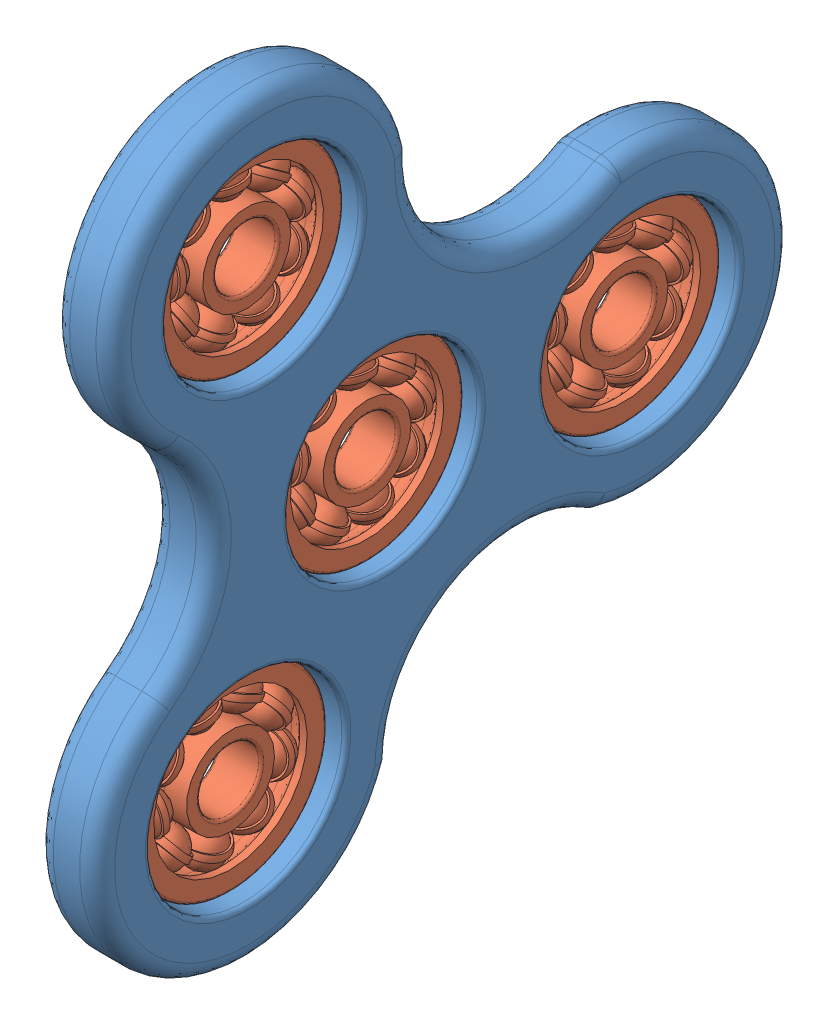
SolidWorks assembly asemspinner, configuration Default. Lengths in mm.
Overall size (7.23 89.78 83.98).
5 component instances, 2 part files, 10 mates.
Components (placement in the parent):
- fildeg spiner-1: fildeg spiner [Default] at (3.5 0 0) x (0 0.998158 -0.060674) z (1 0 0) size (85.14 78.96 7.23)
- FINAl_SPINNER-1: FINAl_SPINNER [BS 6267 ABB - 827 - Full,DE,AC,Full_68] at (2.5 -24.815 15.5658) x (1 0 0) z (0 -0.702747 -0.71144) size (5 22 22)
- FINAl_SPINNER-2: FINAl_SPINNER [BS 6267 ABB - 827 - Full,DE,AC,Full_68] at (2.5 25.8879 13.7075) x (1 0 0) z (0 0.595884 0.803071) size (5 22 22)
- FINAl_SPINNER-3: FINAl_SPINNER [BS 6267 ABB - 827 - Full,DE,AC,Full_68] at (2.5 -1.0729 -29.2733) x (1 0 0) z (0 0.992473 0.122465) size (5 22 22)
- FINAl_SPINNER-4: FINAl_SPINNER [BS 6267 ABB - 827 - Full,DE,AC,Full_68] at (2.5 0 0) x (1 0 0) z (0 -0.60569 0.795701) size (5 22 22)
Mates (geometry in assembly coordinates):
- Concentric1: concentric anti-aligned: cylinder of fildeg spiner-1 through (7 0 0) axis (-1 0 0) radius 11; cylinder of FINAl_SPINNER-4 through (-18.1375 0 0) axis (1 0 0) radius 5.025
- Coincident2: coincident aligned: plane of fildeg spiner-1 through (0 0 0) normal (-1 0 0); plane of FINAl_SPINNER-4 through (0 7.5393 5.7389) normal (-1 0 0)
- Concentric5: concentric anti-aligned: cylinder of fildeg spiner-1 through (7 25.8879 13.7075) axis (-1 0 0) radius 11.2096; cylinder of FINAl_SPINNER-2 through (-18.1375 25.8879 13.7075) axis (1 0 0) radius 11
- Coincident3: coincident aligned: plane of fildeg spiner-1 through (0 0 0) normal (-1 0 0); plane of FINAl_SPINNER-2 through (0 33.497 8.0615) normal (-1 0 0)
- Concentric6: concentric anti-aligned: cylinder of fildeg spiner-1 through (7 -1.0729 -29.2733) axis (-1 0 0) radius 11.2096; cylinder of FINAl_SPINNER-3 through (-18.1375 -1.0729 -29.2733) axis (1 0 0) radius 11
- Coincident4: coincident aligned: plane of fildeg spiner-1 through (0 0 0) normal (-1 0 0); plane of FINAl_SPINNER-3 through (0 0.0874 -38.677) normal (-1 0 0)
- Concentric7: concentric anti-aligned: cylinder of fildeg spiner-1 through (7 -24.815 15.5658) axis (-1 0 0) radius 11.2096; cylinder of FINAl_SPINNER-1 through (-18.1375 -24.815 15.5658) axis (1 0 0) radius 11
- Coincident5: coincident aligned: plane of fildeg spiner-1 through (0 0 0) normal (-1 0 0); plane of FINAl_SPINNER-1 through (0 -31.5558 22.2244) normal (-1 0 0)
- Concentric10: concentric aligned: circle of FINAl_SPINNER-4; line of assembly
- Coincident6: coincident anti-aligned: plane of fildeg spiner-1 through (0 0 0) normal (-1 0 0); plane of assembly through (0 0 0) normal (1 0 0)
